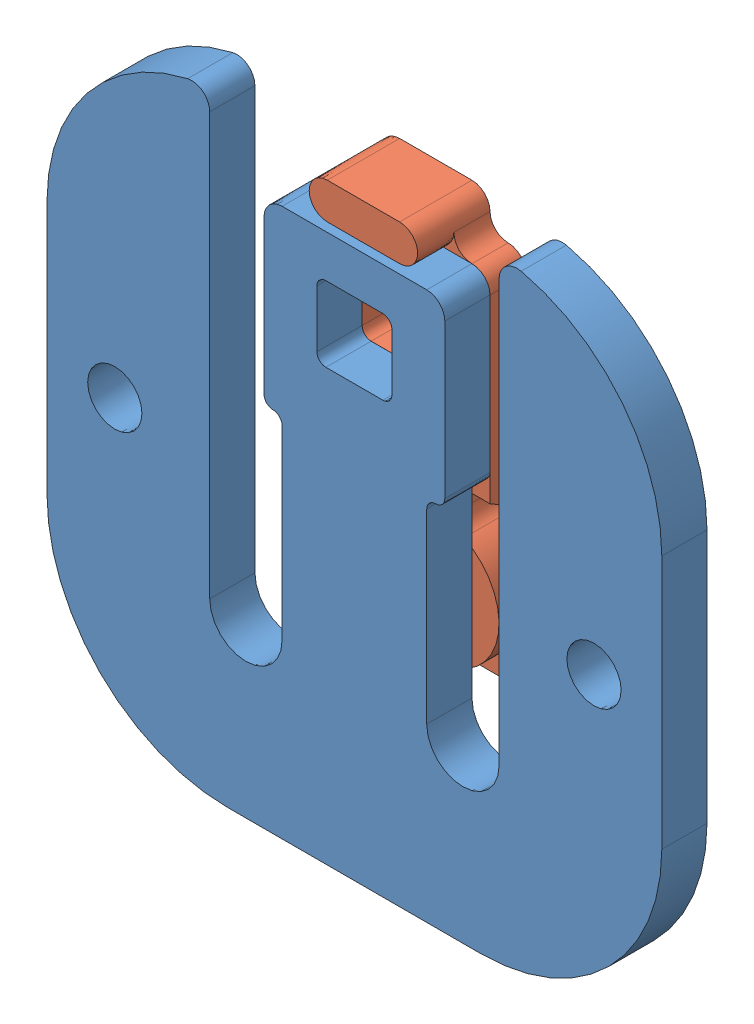
SolidWorks assembly 微型压力传感器_1_2, configuration 默认. Lengths in mm.
Overall size (34 33.83 9.5).
2 component instances, 2 part files, 0 mates.
Components (placement in the parent):
- CS_应变片-1: CS_应变片 [默认] at (2.3913 -0.6048 32.75) size (34 33.83 2.5)
- CS_固定片1_2-1: CS_固定片1_2 [默认] at (2.3913 0.6952 32.75) x (0 0 -1) z (0 -1 0) size (9 10 26)
